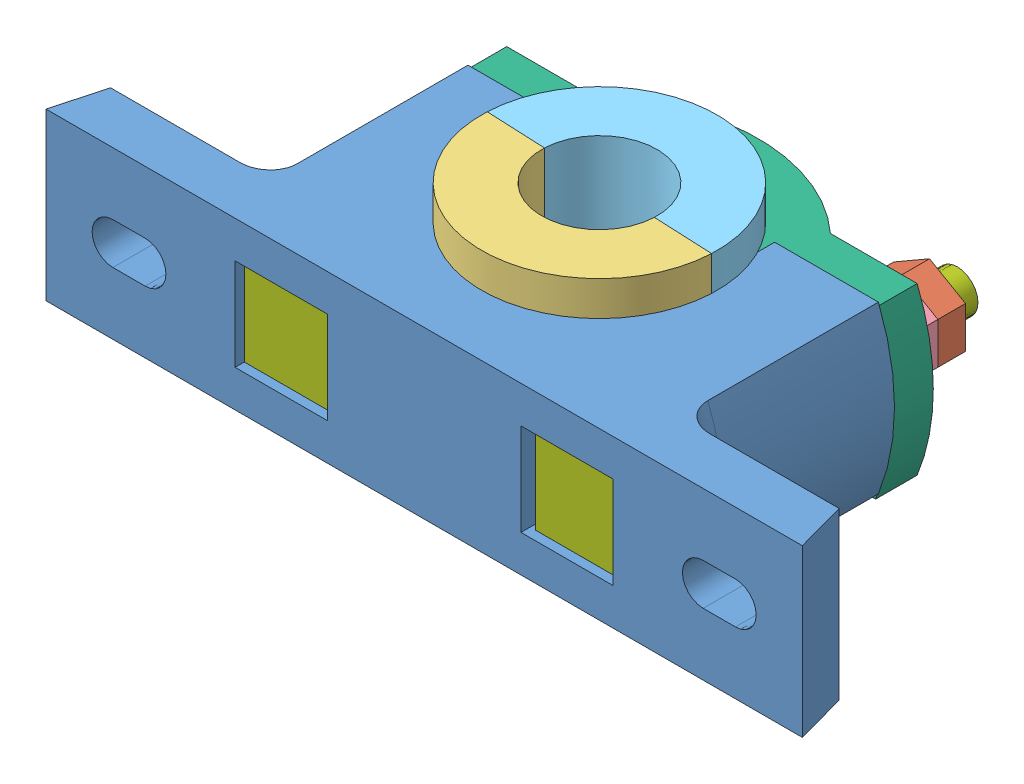
SolidWorks assembly Assem1, configuration Default. Lengths in mm.
Overall size (164 51 84).
10 component instances, 7 part files, 16 mates.
Components (placement in the parent):
- casing-1: casing [Default] at (146.4956 15.0757 36.4226) size (164 36 54)
- Lock Nut-1: Lock Nut [Default] at (114.9001 13.765 -35.5774) x (1 0 0) z (0 1 0) size (15.59 6 18)
- lower brass-1: lower brass [Default] at (146.4956 15.7566 -1.5774) x (0 1 0) z (0.998988 0 0.044972) size (51 25.5 51)
- Nut-1: Nut [Default] at (114.9001 13.765 -26.5774) x (1 0 0) z (0 1 0) size (15.59 9 18)
- Upper Brasses-2: Upper Brasses [Default] at (146.4956 15.7566 -1.5774) x (0 1 0) z (-0.998988 0 -0.044972) size (51 25.5 51)
- plumer cap-3: plumer cap [Default] at (145.9001 13.765 -4.5774) x (1 0 0) z (0 1 0) size (96 32 36)
- bolt-2: bolt [Default] at (114.9001 13.765 34.4226) x (-1 0 0) z (0 -1 0) size (19 82 19)
- bolt-3: bolt [Default] at (178.0911 13.765 34.4226) x (1 0 0) z (0 1 0) size (19 82 19)
- Lock Nut-2: Lock Nut [Default] at (178.0911 13.765 -35.5774) x (-1 0 0) z (0 -1 0) size (15.59 6 18)
- Nut-2: Nut [Default] at (178.0911 13.765 -26.5774) x (-1 0 0) z (0 -1 0) size (15.59 9 18)
Mates (geometry in assembly coordinates):
- Parallel7: parallel anti-aligned: cylinder of casing-1 through (146.4956 33.0757 -1.5774) axis (0 -1 0) radius 19; cylinder of lower brass-1 through (146.4956 15.7566 -1.5774) axis (0 1 0) radius 17.5
- Parallel10: parallel anti-aligned: cylinder of casing-1 through (145.6411 15.7566 17.4034) axis (0.044972 0 -0.998988) radius 3; cylinder of lower brass-1 through (146.4957 15.7566 -1.5784) axis (-0.044972 0 0.998988) radius 3
- Concentric20: concentric anti-aligned: cylinder of casing-1 through (146.4956 33.0757 -1.5774) axis (0 -1 0) radius 19; cylinder of lower brass-1 through (146.4956 15.7566 -1.5774) axis (0 1 0) radius 17.5
- Concentric27: concentric anti-aligned: cylinder of lower brass-1 through (146.4956 15.7566 -1.5774) axis (0 1 0) radius 12.5; cylinder of Upper Brasses-2 through (146.4956 41.2566 -1.5774) axis (0 -1 0) radius 12.5
- Coincident15: coincident anti-aligned: plane of lower brass-1 through (146.4956 15.7566 -1.5774) normal (0.044972 0 -0.998988); plane of Upper Brasses-2 through (146.4956 15.7566 -1.5774) normal (-0.044972 0 0.998988)
- Coincident18: coincident aligned: plane of lower brass-1 through (134.0083 -9.7434 -2.1395) normal (0 -1 0); plane of Upper Brasses-2 through (121.0214 -9.7434 -2.7241) normal (0 -1 0)
- Concentric44: concentric anti-aligned: cylinder of casing-1 through (114.9001 13.765 28.4226) axis (0 0 1) radius 4.5; cylinder of plumer cap-3 through (114.9001 13.765 9.4226) axis (0 0 -1) radius 4.5
- Coincident31: coincident anti-aligned: plane of casing-1 through (96.4956 33.0757 -17.5774) normal (0 0 -1); plane of plumer cap-3 through (123.9001 31.765 -17.5774) normal (0 0 1)
- Concentric46: concentric aligned: cylinder of casing-1 through (114.9001 13.765 28.4226) axis (0 0 1) radius 4.5; cylinder of bolt-2 through (114.9001 13.765 -47.5774) axis (0 0 1) radius 4.5
- Parallel31: parallel anti-aligned: plane of casing-1 through (125.4956 5.0757 28.4226) normal (0 1 0); plane of bolt-2 through (105.4001 4.265 28.4226) normal (0 -1 0)
- Coincident36: coincident anti-aligned: plane of casing-1 through (146.4956 15.0757 28.4226) normal (0 0 1); plane of bolt-2 through (114.9001 13.765 28.4226) normal (0 0 -1)
- Concentric47: concentric anti-aligned: cylinder of Nut-1 through (114.9001 13.765 -26.5774) axis (0 0 -1) radius 4.5; cylinder of bolt-2 through (114.9001 13.765 -47.5774) axis (0 0 1) radius 4.5
- Concentric48: concentric anti-aligned: cylinder of Nut-1 through (114.9001 13.765 -26.5774) axis (0 0 -1) radius 4.5; cylinder of bolt-2 through (114.9001 13.765 -47.5774) axis (0 0 1) radius 4.5
- Coincident37: coincident anti-aligned: plane of Nut-1 through (114.9001 13.765 -26.5774) normal (0 0 1); plane of plumer cap-3 through (95.9001 31.765 -26.5774) normal (0 0 -1)
- Coincident39: coincident anti-aligned: circle of Lock Nut-1; cylinder of bolt-2 through (114.9001 13.765 -47.5774) axis (0 0 1) radius 4.5
- Coincident40: coincident anti-aligned: plane of Lock Nut-1 through (114.9001 13.765 -35.5774) normal (0 0 1); plane of Nut-1 through (114.9001 13.765 -35.5774) normal (0 0 -1)
